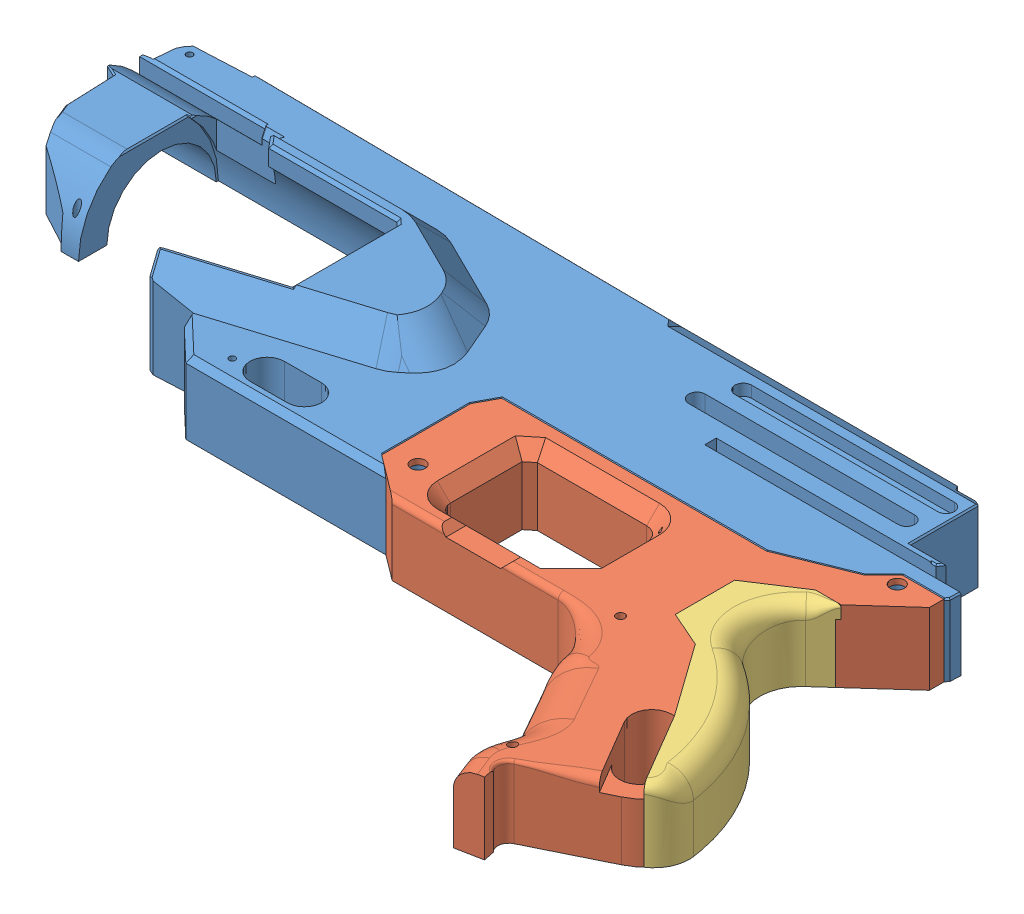
SolidWorks assembly Casing Assembly, configuration Default. Lengths in mm.
Overall size (316.26 35.4 180.45).
3 component instances, 3 part files, 6 mates.
Components (placement in the parent):
- BlueCasing-1: BlueCasing [Default] at (-617.0884 -4.4748 593.468) size (308.07 35.4 103.82)
- Light Grey Handle-1: Light Grey Handle [Default] at (-617.0884 -4.4748 593.468) x (1 0 0) z (0 1 0) size (148.12 135.48 25.59)
- DarkGreyHandle-1: DarkGreyHandle [Default] at (-617.0884 -4.4748 593.468) x (1 0 0) z (0 1 0) size (51.4 89.36 25.17)
Mates (geometry in assembly coordinates):
- Coincident1: coincident anti-aligned: plane of BlueCasing-1 through (2.3845 18.5252 15.7179) normal (0 1 0); plane of Light Grey Handle-1 through (2.3845 18.5252 15.7179) normal (0 -1 0)
- Coincident2: coincident anti-aligned: plane of BlueCasing-1 through (86.396 20.5252 21.3029) normal (0 0 1); plane of Light Grey Handle-1 through (62.6014 18.5252 21.3029) normal (0 0 -1)
- Coincident6: coincident anti-aligned: plane of BlueCasing-1 through (-1.6507 20.5252 35.0907) normal (1 0 0); plane of Light Grey Handle-1 through (-1.6507 18.5252 18.5821) normal (-1 0 0)
- Coincident7: coincident anti-aligned: plane of Light Grey Handle-1 through (121.9593 16.0252 83.046) normal (0 1 0); plane of DarkGreyHandle-1 through (140.7748 16.0252 98.0877) normal (0 -1 0)
- Coincident8: coincident anti-aligned: plane of Light Grey Handle-1 through (92.4191 16.0252 24.652) normal (1 0 0); plane of DarkGreyHandle-1 through (92.4191 20.5252 24.652) normal (-1 0 0)
- Coincident9: coincident anti-aligned: plane of Light Grey Handle-1 through (118.3845 16.0252 13.5348) normal (0 0 1); plane of DarkGreyHandle-1 through (118.3845 20.5252 13.5348) normal (0 0 -1)
